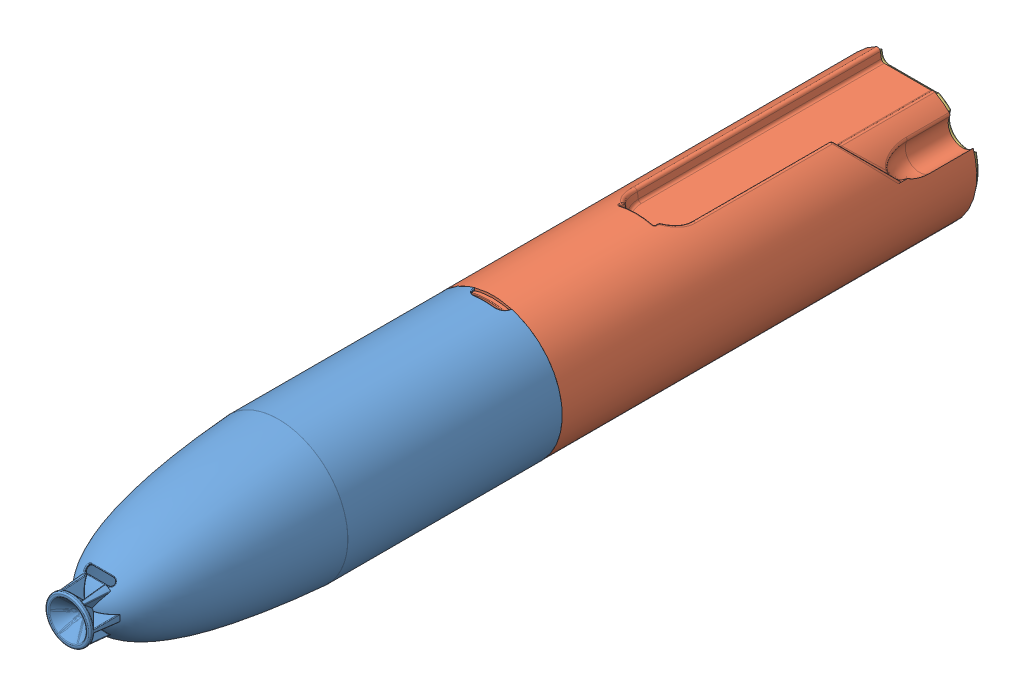
SolidWorks assembly recoverySystem, configuration Default. Lengths in mm.
Overall size (139.8 130.13 751.33).
4 component instances, 4 part files, 8 mates.
Components (placement in the parent):
- drougeCup-1: drougeCup [Default] at origin size (123.19 130.13 378.32)
- mainCup-1: mainCup [Default] at (0 0 -330.2) x (-1 0 0) z (0 1 0) size (139.8 372.11 123.19)
- pizzaTable-1: pizzaTable [Default] at (0 0 -374.65) x (0.5 -0.866025 0) z (-0.866025 -0.5 0) size (145.61 100.4 126.74) (hidden)
- mainPlug-1: mainPlug [Default] at (0.1112 -0.2572 -442.8298) x (-1 0 0) z (0 0 -1) size (116.59 109.66 5.33)
Mates (geometry in assembly coordinates):
- Concentric1: concentric anti-aligned: cylinder of Cup_Chute_Drogue^ERS_v3.0-1 through (0 0 -50.7445) axis (0 0 -1) radius 61.595; cylinder of mainCup-1 through (0 0 -340.658) axis (0 0 1) radius 59.563
- Coincident1: coincident anti-aligned: plane of Cup_Chute_Drogue^ERS_v3.0-1 through (0 61.595 0) normal (0 0 -1); plane of mainCup-1 through (0 0 0) normal (0 0 1)
- Concentric3: concentric aligned: cylinder of mainCup-1 through (0 0 -50.8) axis (0 0 -1) radius 61.595; cylinder of PIZZA_v4.2-1 through (0 0 -368.3) axis (0 0 -1) radius 61.595
- Coincident2: coincident anti-aligned: plane of mainCup-1 through (23.137 43.7938 -368.3) normal (0 0 -1); plane of PIZZA_v4.2-1 through (0 0 -368.3) normal (0 0 1)
- Parallel1: parallel aligned: plane of mainCup-1 through (0 45.72 -330.2) normal (0 1 0); plane of PIZZA_v4.2-1 through (0 46.482 -368.3) normal (0 1 0)
- Coincident4: coincident aligned: plane of Cup_Chute_Drogue^ERS_v3.0-1 through (0 0 0) normal (0 1 0); plane of mainCup-1 through (0 0 -330.2) normal (0 1 0)
- Concentric5: concentric aligned: cylinder of mainCup-1 through (0 0 -368.3) axis (0 0 1) radius 59.563; cylinder of mainPlug-1 through (0 0 -373.38) axis (0 0 1) radius 58.293
- Parallel4: parallel aligned: plane of mainCup-1 through (0 45.72 -330.2) normal (0 1 0); plane of mainPlug-1 through (-20.7163 42.418 -373.38) normal (0 1 0)
